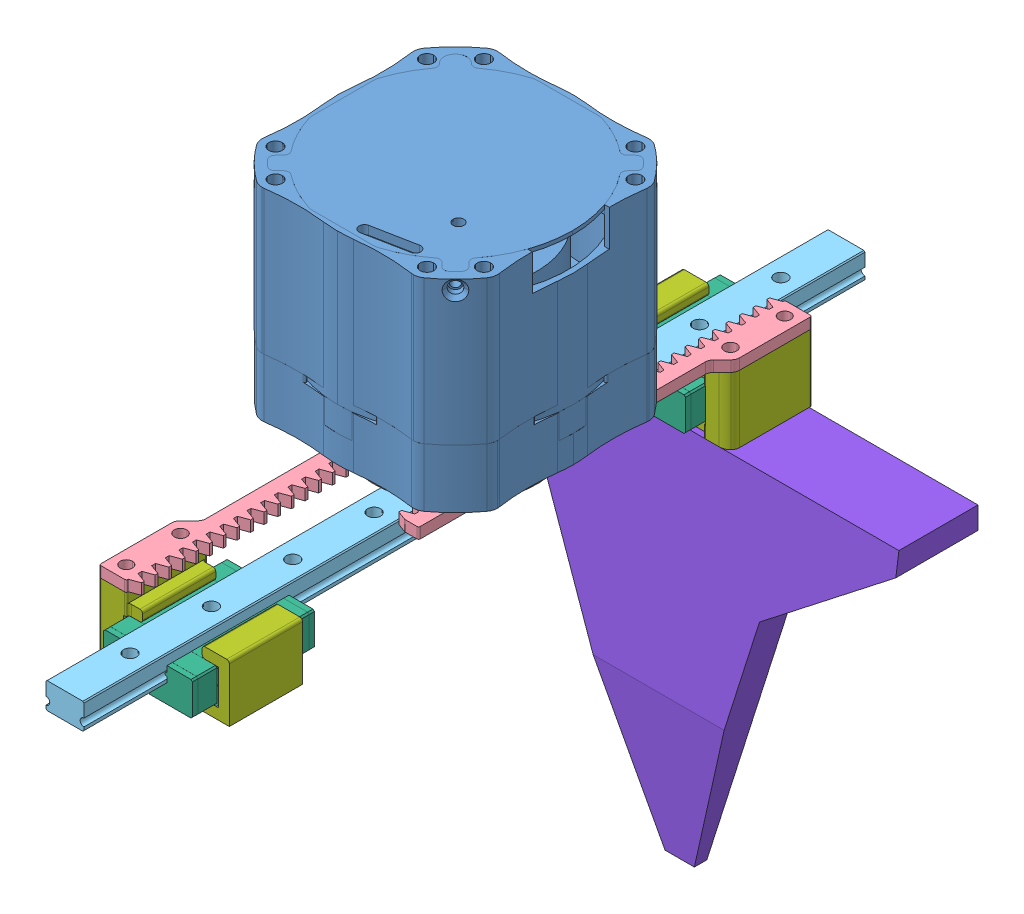
SolidWorks assembly 装配体_爪子, configuration 默认. Lengths in mm.
Overall size (70 127.73 144).
11 component instances, 9 part files, 34 mates.
Components (placement in the parent):
- 4538_32-1: 4538_32 [默认] at (-2.7737 -4.5908 43.5) size (43.5 40.8 43.5)
- 齿轮与电机连接件-1: 齿轮与电机连接件 [默认] at (-2.7737 -21.8908 43.5) x (-0.151358 0 -0.988479) z (0.988479 0 -0.151358) size (30 3 30)
- 夹爪齿轮_0.8_18_20°.step-1: 夹爪齿轮_0.8_18_20°.step [默认] at (-2.7737 -21.8908 43.5) x (0 -1 0) z (-0.931727 0 -0.363159) size (3 15.82 16)
- 夹爪齿条_0.8_2.0_3.5_70_20°.step-1: 夹爪齿条_0.8_2.0_3.5_70_20°.step [默认] at (-13.2727 -24.3908 96.1918) x (0 0 -1) z (0 -1 0) size (70 6.8 2)
- 夹爪齿条_0.8_2.0_3.5_70_20°.step-2: 夹爪齿条_0.8_2.0_3.5_70_20°.step [默认] at (7.7253 -24.3908 -9.216) x (0 0 1) z (0 -1 0) size (70 6.8 2)
- 滑条-1: 滑条 [默认] at (-2.7737 -28.7868 115.5) x (0 0 -1) z (-1 0 0) size (144 9 9)
- 滑块-1: 滑块 [默认] at (-2.7737 -31.4888 95.6946) x (0 0 -1) z (-1 0 0) size (22.5 6.5 17)
- 滑块-2: 滑块 [默认] at (-2.7737 -31.4888 4.7812) x (0 0 -1) z (-1 0 0) size (22.5 6.5 17)
- 零件4-1: 零件4 [默认] at (-2.7737 -31.4888 95.6946) x (1 0 0) z (0 1 0) size (23.5 15.09 12.35)
- 零件4-2: 零件4 [默认] at (-2.7737 -31.4888 -8.7188) x (-1 0 0) z (0 1 0) size (23.5 15.09 12.35)
- 爪子-1: 爪子 [默认] at (6.3559 -104.7388 1.2812) x (0 0 1) z (-1 0 0) size (26.46 69.08 70)
Mates (geometry in assembly coordinates):
- 同心1: concentric anti-aligned: cylinder of 4538_32-1 through (-2.7737 -17.9908 43.5) axis (0 1 0) radius 15; cylinder of 齿轮与电机连接件-1 through (-2.7737 -18.8908 43.5) axis (0 -1 0) radius 15
- 重合1: coincident anti-aligned: plane of 4538_32-1 through (-2.7737 -18.8908 43.5) normal (0 -1 0); plane of 齿轮与电机连接件-1 through (-2.7737 -18.8908 43.5) normal (0 1 0)
- 重合2: coincident anti-aligned: plane of 齿轮与电机连接件-1 through (-2.7737 -21.8908 43.5) normal (0 -1 0); plane of 夹爪齿轮_0.8_18_20°.step-1 through (-2.7737 -21.8908 43.5) normal (0 1 0)
- 同心3: concentric anti-aligned: cylinder of 齿轮与电机连接件-1 through (-1.1395 -18.8908 39.3072) axis (0 -1 0) radius 1; cylinder of 夹爪齿轮_0.8_18_20°.step-1 through (-1.1395 -30.8908 39.3072) axis (0 1 0) radius 1
- 同心4: concentric aligned: cylinder of 4538_32-1 through (-2.7737 -17.9908 43.5) axis (0 1 0) radius 15; cylinder of 夹爪齿轮_0.8_18_20°.step-1 through (-2.7737 -71.8909 43.5) axis (0 1 0) radius 1.5
- 平行1: parallel anti-aligned: plane of 夹爪齿条_0.8_2.0_3.5_70_20°.step-1 through (-13.2727 -21.8908 96.1918) normal (-1 0 0)
- 距离1: distance = 0.5 mm aligned: plane of 夹爪齿条_0.8_2.0_3.5_70_20°.step-1 through (-8.9727 -24.3908 96.1918) normal (0 -1 0); plane of 夹爪齿轮_0.8_18_20°.step-1 through (-2.7737 -24.8908 43.5) normal (0 -1 0)
- 重合6: coincident aligned: plane of 夹爪齿条_0.8_2.0_3.5_70_20°.step-1 through (-8.9727 -24.3908 96.1918) normal (0 -1 0); plane of 夹爪齿条_0.8_2.0_3.5_70_20°.step-2 through (3.4253 -24.3908 -9.216) normal (0 -1 0)
- 相切3: tangent anti-aligned: cylinder of 夹爪齿轮_0.8_18_20°.step-1 through (-2.7737 -24.8908 43.5) axis (0 1 0) radius 6.199; plane of 夹爪齿条_0.8_2.0_3.5_70_20°.step-2 through (3.4253 -21.8908 -9.216) normal (-1 0 0)
- 相切4: tangent anti-aligned: cylinder of 夹爪齿轮_0.8_18_20°.step-1 through (-2.7737 -24.8908 43.5) axis (0 1 0) radius 6.199; plane of 夹爪齿条_0.8_2.0_3.5_70_20°.step-1 through (-8.9727 -21.8908 96.1918) normal (1 0 0)
- 平行2: parallel anti-aligned: plane of 夹爪齿条_0.8_2.0_3.5_70_20°.step-1 through (-13.2727 -21.8908 96.1918) normal (-1 0 0); plane of 夹爪齿条_0.8_2.0_3.5_70_20°.step-2 through (7.7253 -21.8908 -9.216) normal (1 0 0)
- RackPinionMate2: rack pinion = 14.28 mm: line of 夹爪齿条_0.8_2.0_3.5_70_20°.step-1 through (-8.9727 -24.3908 26.8296) axis (0 0 1); circle of 夹爪齿轮_0.8_18_20°.step-1
- RackPinionMate3: rack pinion = 14.26 mm: line of 夹爪齿条_0.8_2.0_3.5_70_20°.step-2 through (3.4253 -24.3908 60.1461) axis (0 0 -1); circle of 夹爪齿轮_0.8_18_20°.step-1
- 平行3: parallel aligned: plane of 夹爪齿条_0.8_2.0_3.5_70_20°.step-1 through (-13.2727 -21.8908 96.1918) normal (-1 0 0); plane of 滑条-1 through (-6.2717 -28.9888 -28.5) normal (-1 0 0)
- 同心5: concentric anti-aligned: cylinder of 夹爪齿轮_0.8_18_20°.step-1 through (-2.7737 -71.8909 43.5) axis (0 1 0) radius 1.5; cylinder of 滑条-1 through (-2.7737 -26.3908 43.5) axis (0 -1 0) radius 1.2
- 同心6: concentric anti-aligned: cylinder of 滑条-1 through (0.7243 -29.6888 -28.5) axis (0 0 1) radius 0.7; cylinder of 滑块-2 through (0.7243 -29.6888 16.744) axis (0 0 -1) radius 0.35
- 同心7: concentric anti-aligned: cylinder of 滑条-1 through (-6.2717 -29.6888 -28.5) axis (0 0 1) radius 0.7; cylinder of 滑块-2 through (-6.2717 -29.6888 16.744) axis (0 0 -1) radius 0.35
- 同心8: concentric anti-aligned: cylinder of 滑条-1 through (0.7243 -29.6888 -28.5) axis (0 0 1) radius 0.7; cylinder of 滑块-1 through (0.7243 -29.6888 107.6574) axis (0 0 -1) radius 0.35
- 同心9: concentric anti-aligned: cylinder of 滑条-1 through (-6.2717 -29.6888 -28.5) axis (0 0 1) radius 0.7; cylinder of 滑块-1 through (-6.2717 -29.6888 107.6574) axis (0 0 -1) radius 0.35
- LimitDistance1: limit distance = 15.2812 mm aligned: plane of 滑块-2 through (-2.7737 -31.4888 -13.2188) normal (0 0 -1); plane of 滑条-1 through (0.7243 -29.6888 -28.5) normal (0 0 -1)
- LimitDistance2: limit distance = 15.3054 mm aligned: plane of 滑条-1 through (0.7243 -29.6888 115.5) normal (0 0 1); plane of 滑块-1 through (-2.7737 -31.4888 100.1946) normal (0 0 1)
- 距离4: distance = 1.5 mm anti-aligned: plane of 滑条-1 through (0.5263 -26.3908 -28.5) normal (0 1 0); plane of 夹爪齿轮_0.8_18_20°.step-1 through (-2.7737 -24.8908 43.5) normal (0 -1 0)
- LimitDistance3: limit distance = 19.284 mm aligned: plane of 夹爪齿条_0.8_2.0_3.5_70_20°.step-2 through (7.7253 -21.8908 -9.216) normal (0 0 -1); plane of 滑条-1 through (0.7243 -29.6888 -28.5) normal (0 0 -1)
- 重合15: coincident anti-aligned: plane of 滑块-1 through (-10.8707 -34.7388 82.1946) normal (0 -1 0); plane of 零件4-1 through (-11.2737 -34.7388 82.1946) normal (0 1 0)
- 同心10: concentric anti-aligned: cylinder of 滑块-1 through (-8.7737 -32.2388 92.9446) axis (0 -1 0) radius 0.9; cylinder of 零件4-1 through (-8.7737 -38.7388 92.9446) axis (0 1 0) radius 1
- 同心11: concentric anti-aligned: cylinder of 滑块-1 through (-8.7737 -32.2388 84.9446) axis (0 -1 0) radius 0.9; cylinder of 零件4-1 through (-8.7737 -38.7388 84.9446) axis (0 1 0) radius 1
- 同心14: concentric anti-aligned: cylinder of 夹爪齿条_0.8_2.0_3.5_70_20°.step-1 through (-13.2727 -24.3908 93.6918) axis (0 1 0) radius 1.1186; cylinder of 零件4-1 through (-13.2727 -22.3908 93.6918) axis (0 -1 0) radius 1.1186
- 同心15: concentric anti-aligned: cylinder of 滑块-2 through (3.2263 -32.2388 2.0312) axis (0 -1 0) radius 0.9; cylinder of 零件4-2 through (3.2263 -38.7388 2.0312) axis (0 1 0) radius 1
- 同心16: concentric anti-aligned: cylinder of 滑块-2 through (-8.7737 -32.2388 -5.9688) axis (0 -1 0) radius 0.9; cylinder of 零件4-2 through (-8.7737 -38.7388 -5.9688) axis (0 1 0) radius 1
- 重合17: coincident anti-aligned: plane of 滑块-2 through (-10.8707 -34.7388 -8.7188) normal (0 -1 0); plane of 零件4-2 through (5.7263 -34.7388 4.7812) normal (0 1 0)
- 同心17: concentric anti-aligned: cylinder of 夹爪齿条_0.8_2.0_3.5_70_20°.step-2 through (7.7253 -24.3908 -6.716) axis (0 1 0) radius 1.1186; cylinder of 零件4-2 through (7.7253 -22.3908 -6.716) axis (0 -1 0) radius 1.1186
- LimitDistance4: limit distance = 68.4134 mm anti-aligned: plane of 滑块-1 through (-2.7737 -31.4888 77.6946) normal (0 0 -1); plane of 滑块-2 through (-2.7737 -31.4888 9.2812) normal (0 0 1)
- 重合19: coincident aligned: plane of 零件4-2 through (-2.7737 -31.4888 -8.7188) normal (0 0 -1); plane of 爪子-1 through (41.3559 -36.7388 -8.7188) normal (0 0 -1)
- 重合20: coincident anti-aligned: plane of 零件4-2 through (7.7263 -36.7388 4.7812) normal (0 -1 0); plane of 爪子-1 through (6.3559 -36.7388 1.2812) normal (0 1 0)
